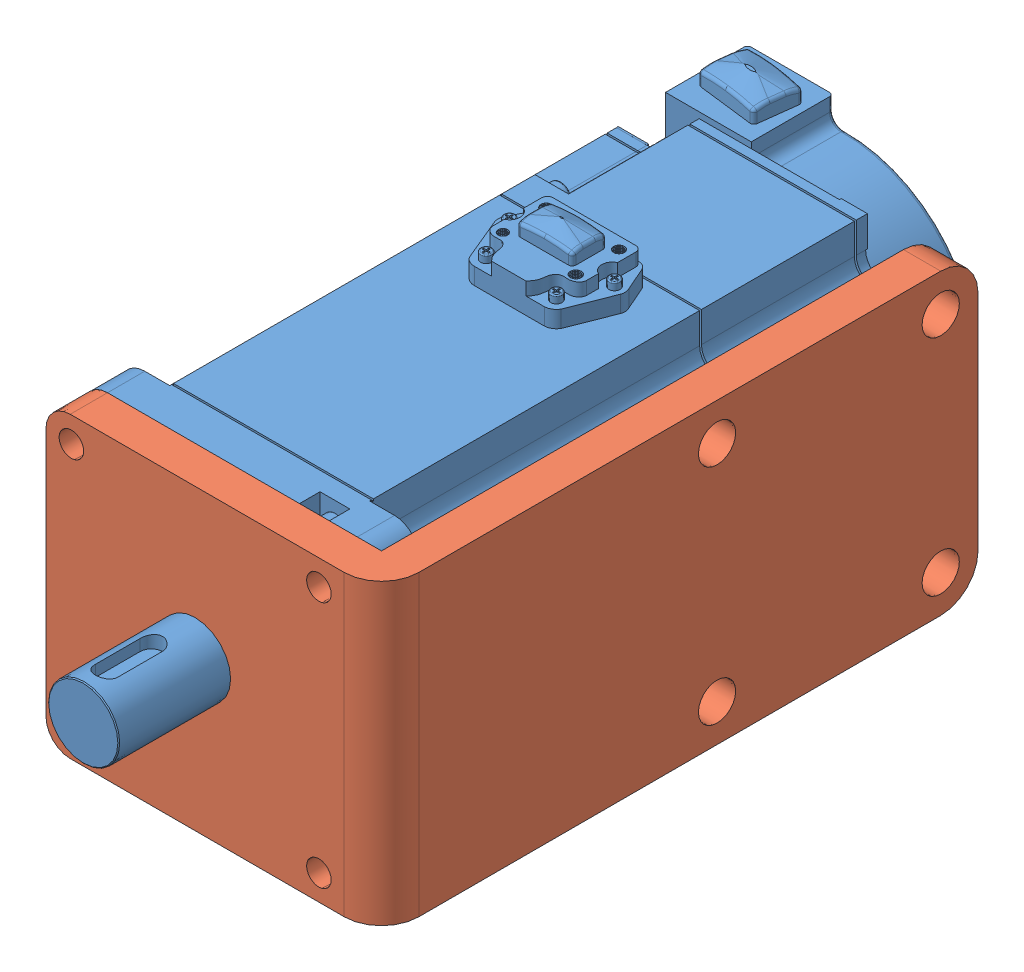
SolidWorks assembly Transmission, configuration Default. Lengths in mm.
Overall size (90.02 93.62 208).
2 component instances, 2 part files, 3 mates.
Components (placement in the parent):
- Servo Motor-1: Servo Motor [Default] at (88.6493 127.466 174.1921) size (80.05 93.62 208)
- Flange-1: Flange [Default] at (93.6493 127.466 194.1921) x (1 0 0) z (0 1 0) size (90 160 80)
Mates (geometry in assembly coordinates):
- Coincident2: coincident anti-aligned: plane of Servo Motor-1 through (55.1493 93.966 184.1921) normal (0 0 1); plane of Flange-1 through (93.6493 127.466 184.1921) normal (0 0 -1)
- Coincident3: coincident aligned: plane of Servo Motor-1 through (55.1493 167.466 184.1921) normal (0 1 0); plane of Flange-1 through (48.6493 167.466 184.1921) normal (0 1 0)
- Coincident4: coincident aligned: plane of Servo Motor-1 through (48.6493 160.966 184.1921) normal (-1 0 0); plane of Flange-1 through (48.6493 87.466 184.1921) normal (-1 0 0)
